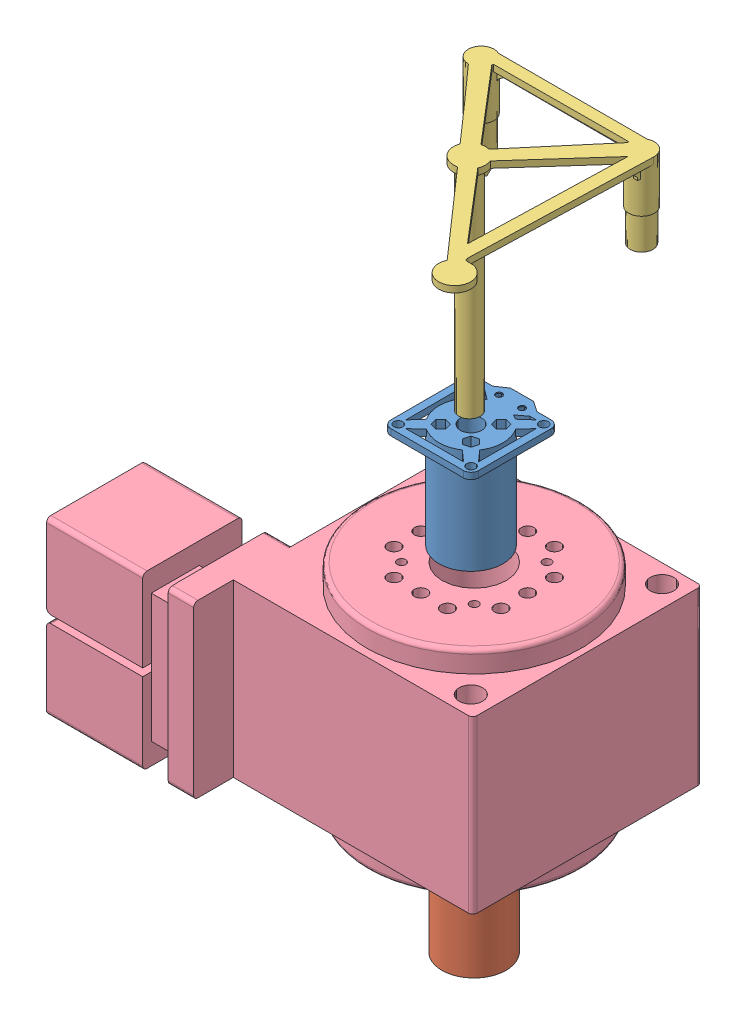
SolidWorks assembly 装配体1, configuration 默认. Lengths in mm.
Overall size (180.71 324.39 125.72).
4 component instances, 4 part files, 0 mates.
Components (placement in the parent):
- DiodeBase_Half_1-1: DiodeBase_Half_1 [默认] at (-114.9536 85.8164 33.8844) size (41 49 44.38)
- DiodeBase_Half_2-1: DiodeBase_Half_2 [默认] at (-180.6234 -83.168 31.8598) size (30 46 30)
- TriMirror-1: TriMirror [默认] at (-138.825 195.1988 0.9112) size (94.81 103.02 107.19)
- 零件_转台模型-1: 零件_转台模型 [默认] at (-120.1754 -57.5964 41.4691) size (180.71 100 125.72)
